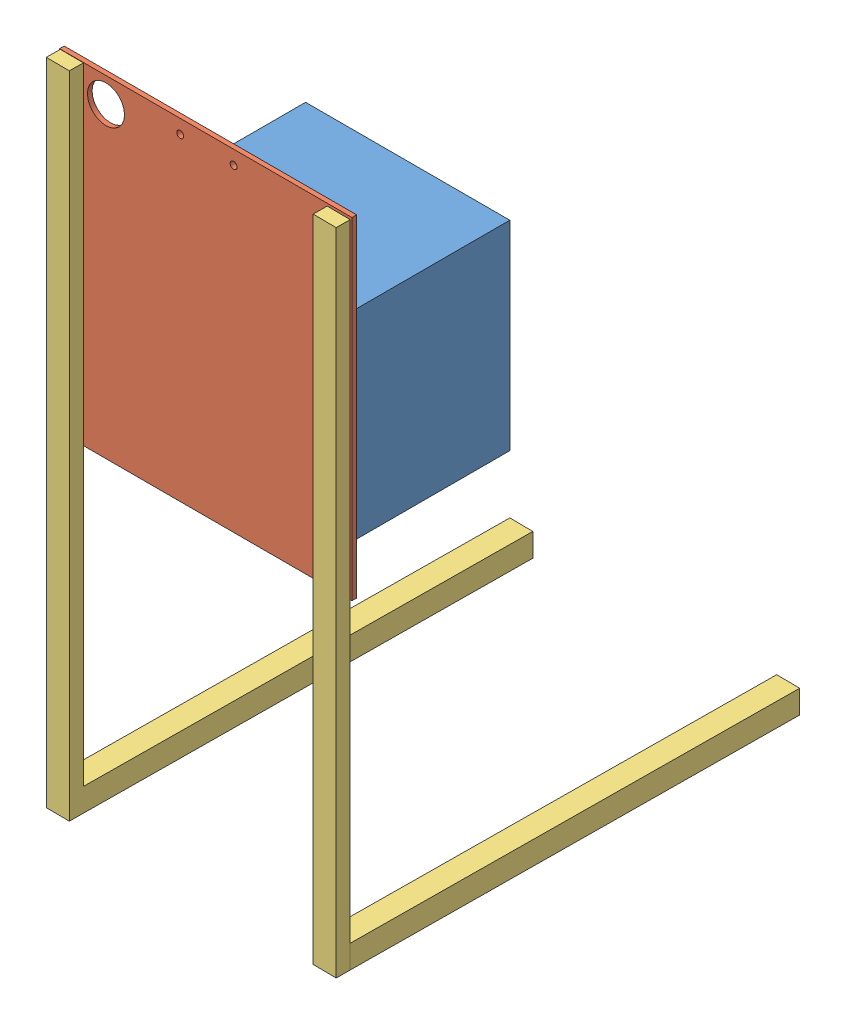
SolidWorks assembly Oven_Design, configuration Default. Lengths in mm.
Overall size (406.59 889.09 632.12).
4 component instances, 4 part files, 4 mates.
Components (placement in the parent):
- Furnace^Oven_Design-1: Furnace^Oven_Design [Default] x (1 0 0) z (0 1 0) size (279.4 279.4 273.05) (virtual)
- BackBase^Oven_Design-2: BackBase^Oven_Design [Default] at origin size (400.05 454.03 6.35) (virtual)
- OvenStands^Oven_Design-1: OvenStands^Oven_Design [Default] at (-17.979 -435.0617 25.8381) x (-0.999962 0 -0.008727) z (0.008727 0 -0.999962) size (400.05 889 628.65) (virtual)
- InsideFurnaceBase^Oven_Design-1: InsideFurnaceBase^Oven_Design [Default] at (139.0705 1.1812 -139.6425) size (209.55 28.57 209.55) (virtual)
Mates (geometry in assembly coordinates):
- InPlace1: in place: plane of Furnace^Oven_Design-1 through (0 0 0) normal (0 1 0); moOrthogonalPlaneRef_w of Furnace^Oven_Design-1 through (0 0 0) normal (0 0 -1); plane of Furnace^Oven_Design-1 through (0 0 0) normal (1 0 0); unknown of Furnace^Oven_Design-1
- Coincident1: coincident aligned: plane of Furnace^Oven_Design-1; plane of assembly
- Coincident2: coincident aligned: plane of Furnace^Oven_Design-1 through (0 0 0) normal (0 0 -1); moOrthogonalPlaneRef_w of assembly
- Coincident3: coincident anti-aligned: plane of Furnace^Oven_Design-1 through (0 0 0) normal (1 0 0); moOrthogonalPlaneRef_w of assembly
